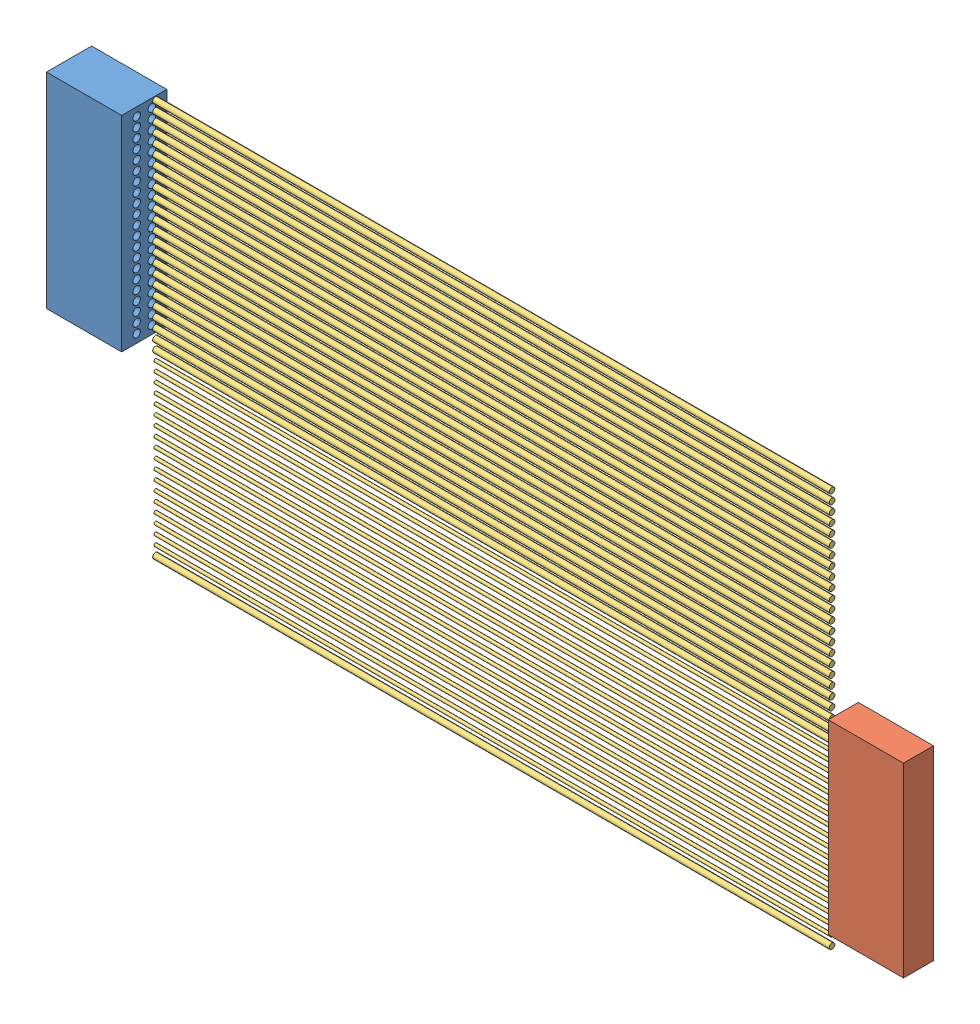
SolidWorks assembly Cable_1-CABLE_HARNESSING_ASSEMBLY, configuration AnnotateFlattenedRoute1 - Default. Lengths in mm.
Overall size (113 53.25 6).
4 component instances, 4 part files, 2 mates.
Components (placement in the parent):
- 42_PIN_CONNECTOR-1: 42_PIN_CONNECTOR [Default] at (-11.5 -28.2989 3) x (0 -1 0) z (1 0 0) size (27.25 6 20)
- 19_PIN_CONNECTOR-1: 19_PIN_CONNECTOR [Default] at (101.5 -51.9205 -2) x (0 -1 0) z (-1 0 0) size (24.75 4 20)
- Cable^Cable_1-CABLE_HARNESSING_ASSEMBLY-1: Cable^Cable_1-CABLE_HARNESSING_ASSEMBLY [Default] at origin size (27.59 85.31 31.4) (suppressed, hidden, virtual)
- Flattened_Cable^Cable_1-CABLE_HARNESSING_ASSEMBLY-1: Flattened_Cable^Cable_1-CABLE_HARNESSING_ASSEMBLY [Default] at origin (virtual)
Mates (geometry in assembly coordinates):
- Coincident931: coincident anti-aligned: plane of STACK_SHELVES-2/FAKE_PCB-3 through (123.7034 157.6 -132.0866) normal (0 1 0); plane of 42_PIN_CONNECTOR-1 through (40.7034 157.6 -60.5866) normal (0 -1 0)
- Coincident9321: coincident anti-aligned: plane of 19_PIN_CONNECTOR-1 through (44.46 76.2 -65.053) normal (0 -1 0); plane of STANDARD_MOUNTING_BRACKET_COILS-1 through (78.2034 76.2 -88.8366) normal (0 1 0)
